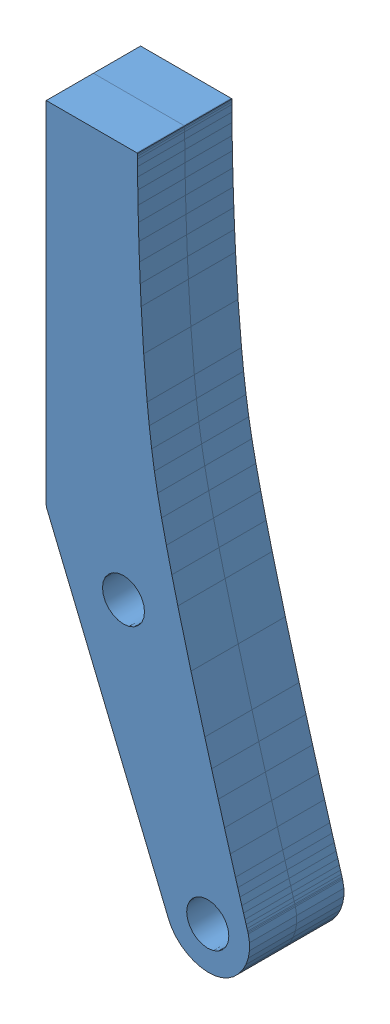
SolidWorks assembly Assem4, configuration Default. Lengths in mm.
Overall size (15.08 50 7).
2 component instances, 1 part files, 0 mates.
Components (placement in the parent):
- gripper3-1: gripper3 [Default] at origin size (15.08 50 3.5)
- gripper3-2: gripper3 [Default] at (0 0 -3.5) size (15.08 50 3.5)
